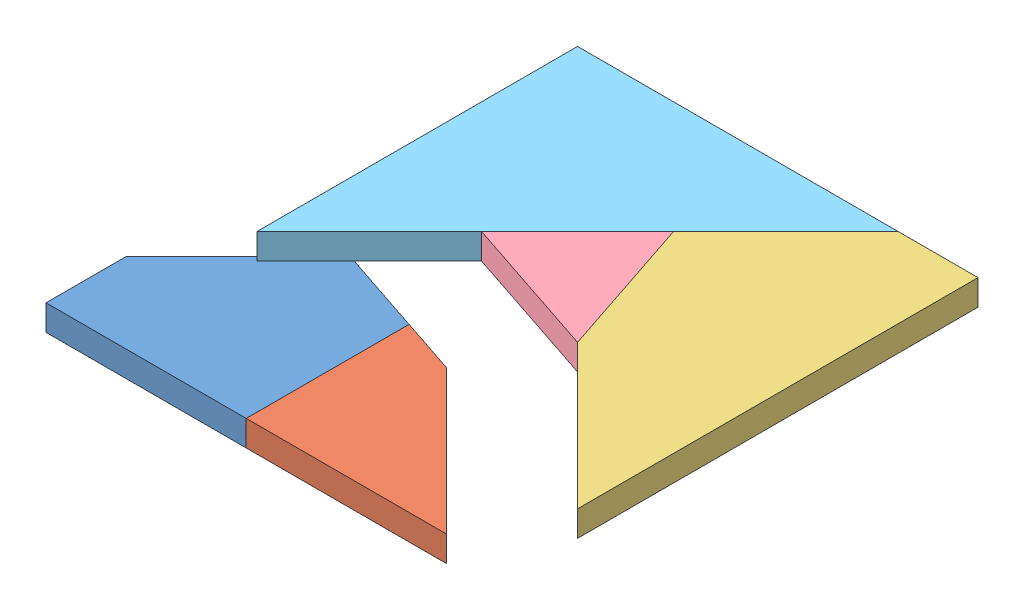
SolidWorks assembly puzzle_1c, configuration Default. Lengths in mm.
Overall size (121.6 17.08 111.13).
7 component instances, 5 part files, 3 mates.
Components (placement in the parent):
- BD-1: BD [Default] at (-19.3285 -9.8492 6.5257) size (100 6.4 48)
  - B-1: B [Default] at origin size (50 6.4 48)
  - D-1: D [Default] at origin size (50 6.4 40.67)
- CE-1: CE [Default] at (2.2755 0.8337 -4.6065) size (72 6.4 100)
  - C-1: C [Default] at origin size (48 6.4 100)
  - E-1: E [Default] at origin size (36 6.4 36)
- A-1: A [Default] at (2.2755 0.8337 -4.6065) size (80 6.4 80)
Mates (geometry in assembly coordinates):
- Coincident2: coincident: plane of CE-1/C-1 through (-7.7245 7.2337 -14.6065) normal (-0.707107 0 -0.707107); plane of A-1 through (-26.5132 7.2337 4.1823) normal (0.707107 0 0.707107)
- Coincident3: coincident: plane of CE-1/C-1 through (2.2755 7.2337 -4.6065) normal (0 1 0); plane of A-1 through (-16.5132 7.2337 14.1823) normal (0 1 0)
- Coincident4: coincident aligned: plane of CE-1/C-1 through (2.2755 7.2337 -104.6065) normal (0 0 -1); plane of A-1 through (2.2755 7.2337 -104.6065) normal (0 0 -1)
